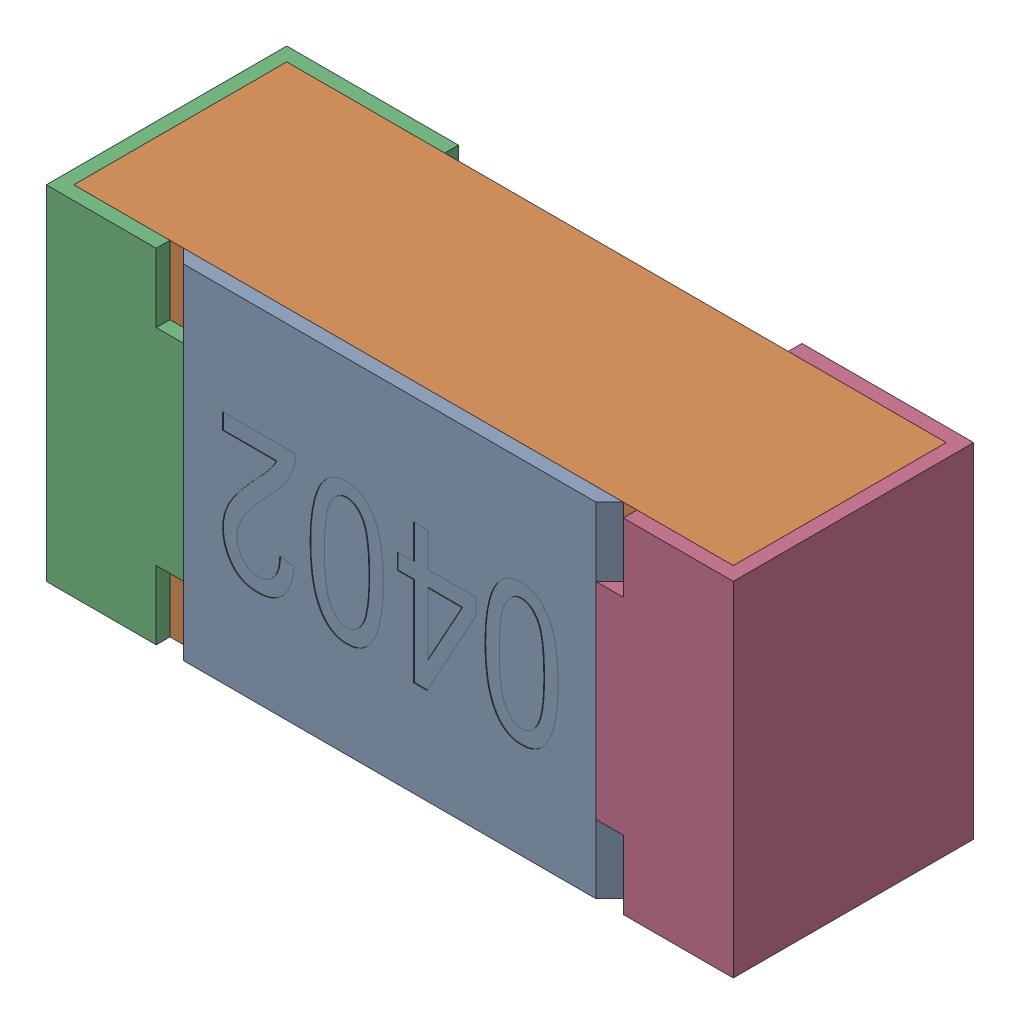
SolidWorks assembly R9, configuration Standard. Lengths in mm.
Overall size (1 0.5 0.35).
5 component instances, 4 part files, 0 mates.
Components (placement in the parent):
- R9-subassembly-1-1: R9-subassembly-1 [Standard] at (6.6999 -13.1 0) x (-1 0 0) z (0 0 1) size (1 0.5 0.35)
  - User Library-R_0402-1: User Library-R_0402 [Standard] at origin size (0.64 0.5 0.02)
  - User Library-R_0402-1-1: User Library-R_0402-1 [Standard] at origin size (0.96 0.5 0.31)
  - User Library-R_0402-2-1: User Library-R_0402-2 [Standard] at origin size (0.25 0.5 0.35)
  - User Library-R_0402-3-1: User Library-R_0402-3 [Standard] at origin size (0.25 0.5 0.35)
